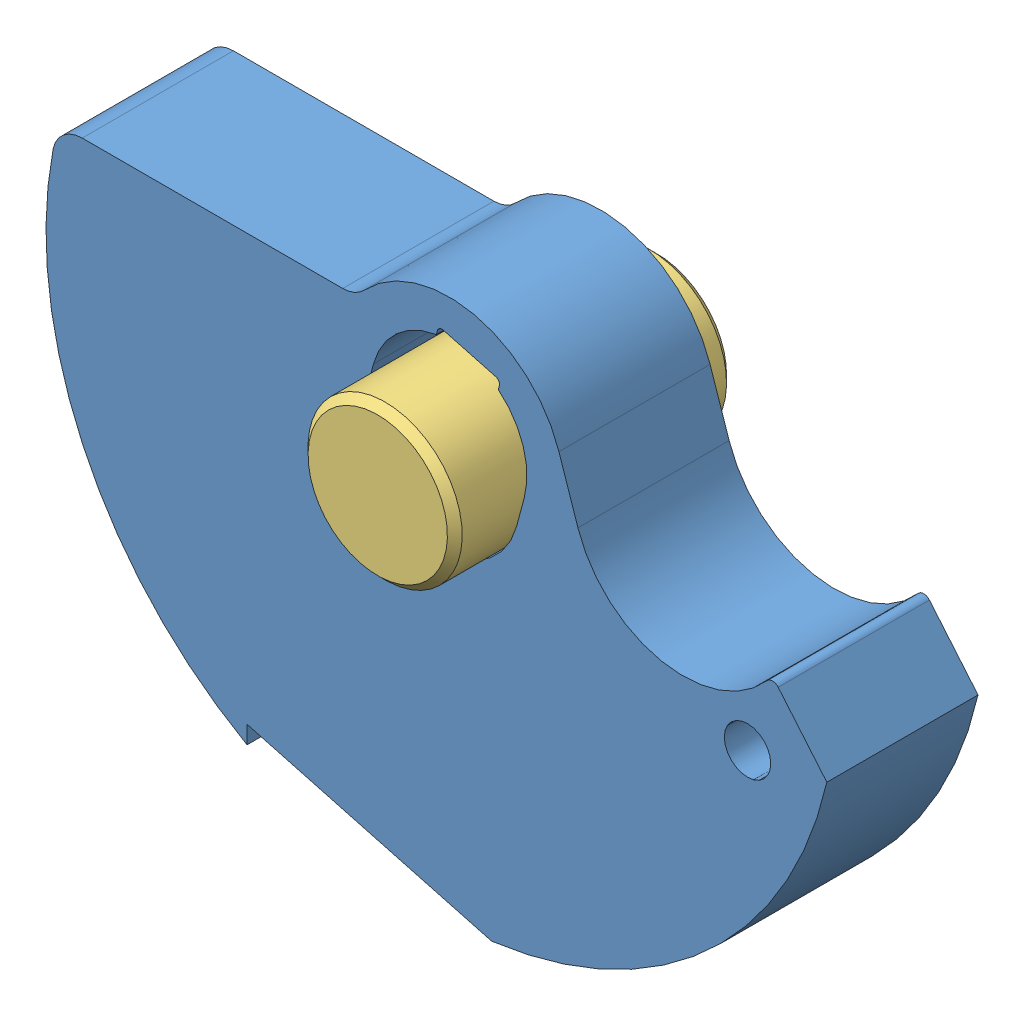
SolidWorks assembly swing bolt subassembly, configuration Default. Lengths in mm.
Overall size (40.14 27.59 14.35).
3 component instances, 3 part files, 6 mates.
Components (placement in the parent):
- 4106-1: 4106 [Default] at (24.5736 24.1411 23.586) size (40.14 27.59 7.77)
- 2979-1: 2979 [Default] at (23.433 19.8844 19.6998) x (0.258819 0.965926 0) z (0.911494 -0.244234 0.330949) size (11.38 3.26 3.28)
- 4105-1: 4105 [Default] at (24.5867 24.1902 26.8626) x (0.965926 -0.258819 0) z (0.258819 0.965926 0) size (7.92 14.35 7.92)
Mates (geometry in assembly coordinates):
- Distance1: distance = 3.8862 mm: plane of 4106-1 through (24.3257 -20.2472 15.8136) normal (0 0 -1); line of 2979-1 through (26.2641 30.4502 19.6998) axis (-0.258819 -0.965926 0)
- Distance2: distance = 1.651 mm: plane of 4106-1 through (11.8651 -16.9084 15.8136) normal (0.965926 -0.258819 0); line of 2979-1 through (26.2641 30.4502 19.6998) axis (-0.258819 -0.965926 0)
- Concentric1: concentric anti-aligned: line of 2979-1 through (26.2641 30.4502 19.6998) axis (-0.258819 -0.965926 0); cylinder of 4105-1 through (25.6139 28.0237 19.6998) axis (0.258819 0.965926 0) radius 1.7272
- Parallel1: parallel aligned: cylinder of 4106-1 through (24.5736 24.1411 15.8136) axis (0 0 1) radius 4.0132; cylinder of 4105-1 through (24.5867 24.1902 12.5116) axis (0 0 1) radius 3.9624
- Distance3: distance = 0 mm: cylinder of 4105-1 through (24.5867 24.1902 12.5116) axis (0 0 1) radius 3.9624; cylinder of 4106-1 through (24.5736 24.1411 15.8136) axis (0 0 1) radius 4.0132
- Coincident1: coincident anti-aligned: plane of 4106-1 through (36.8989 26.6763 15.8136) normal (-0.258819 -0.965926 0); plane of 2979-1 through (26.033 29.5878 19.6998) normal (0.258819 0.965926 0)
